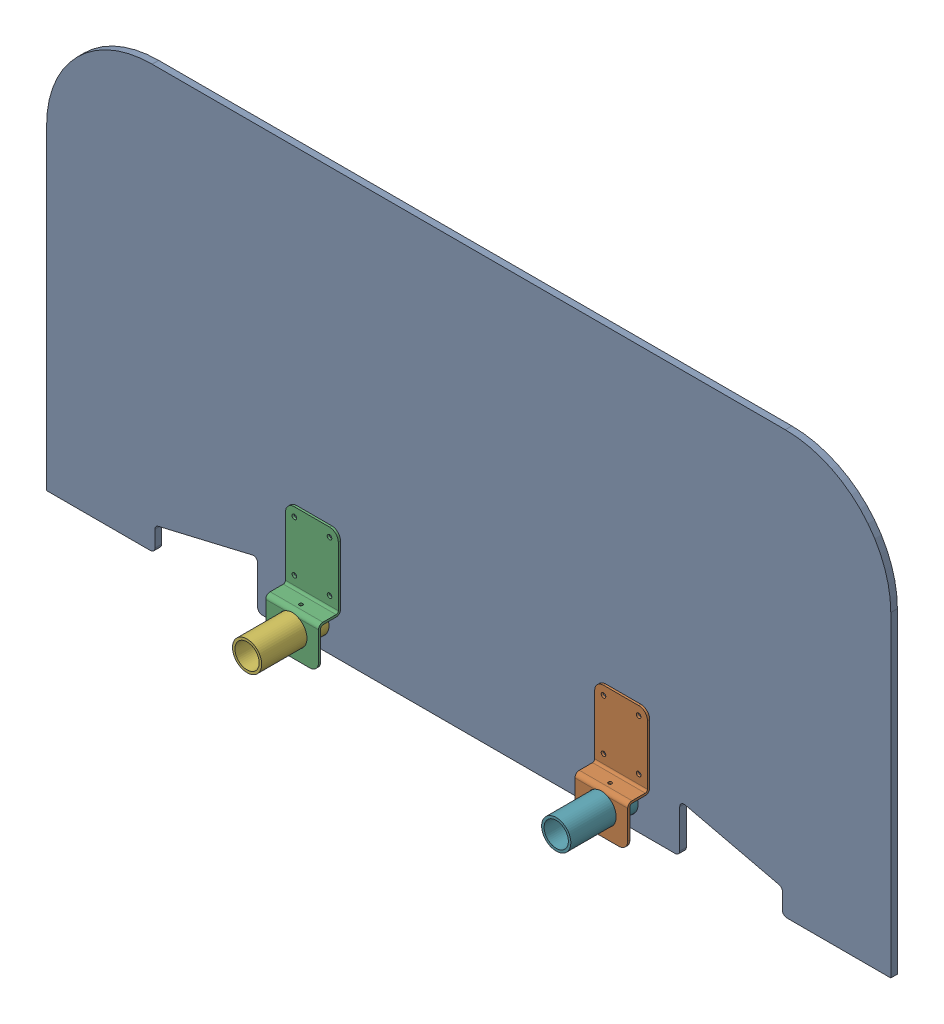
SolidWorks assembly GE-16019_ASM, configuration Default. Lengths in mm.
Overall size (1219.2 609.6 203.2).
7 component instances, 3 part files, 0 mates.
Components (placement in the parent):
- GE-16020-1: GE-16020 [Default] at origin size (1219.2 609.6 9.53)
- GE-16021-1: GE-16021 [Default] at (223.266 -304.8 36.5125) x (1 0 0) z (0 -1 0) size (76.2 31.77 161.93)
- GE-16021-2: GE-16021 [Default] at (-223.266 -304.8 36.5125) x (1 0 0) z (0 -1 0) size (76.2 31.77 161.93)
- GE-16021-3: GE-16021 [Default] at (223.266 -304.8 -36.5125) x (-1 0 0) z (0 -1 0) size (76.2 31.77 161.93)
- GE-16021-4: GE-16021 [Default] at (-223.266 -304.8 -36.5125) x (-1 0 0) z (0 -1 0) size (76.2 31.77 161.93)
- GE-16022-1: GE-16022 [Default] at (-223.266 -269.875 0) x (0 0 -1) z (0 -1 0) size (203.2 42.16 42.16)
- GE-16022-2: GE-16022 [Default] at (223.266 -269.875 0) x (0 0 -1) z (0 -1 0) size (203.2 42.16 42.16)
